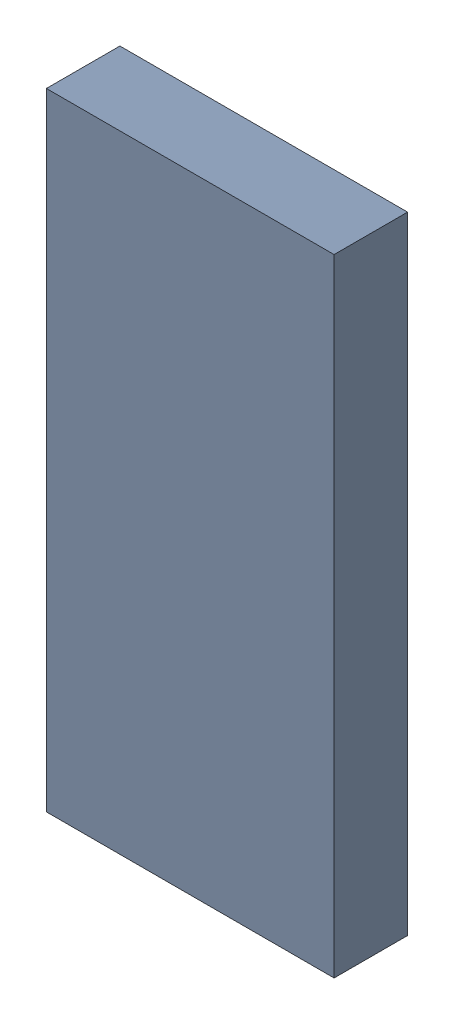
SolidWorks assembly TDA5340_TDA4, configuration Standard. Lengths in mm.
Overall size (4.5 9.8 1.15).
2 component instances, 1 part files, 0 mates.
Components (placement in the parent):
- 885542512-1: 885542512 [Standard] at (0.38 -50.29 0.05) size (4.5 9.8 1.15)
  - Extruded_13-1: Extruded_13 [Standard] at origin size (4.5 9.8 1.15)
